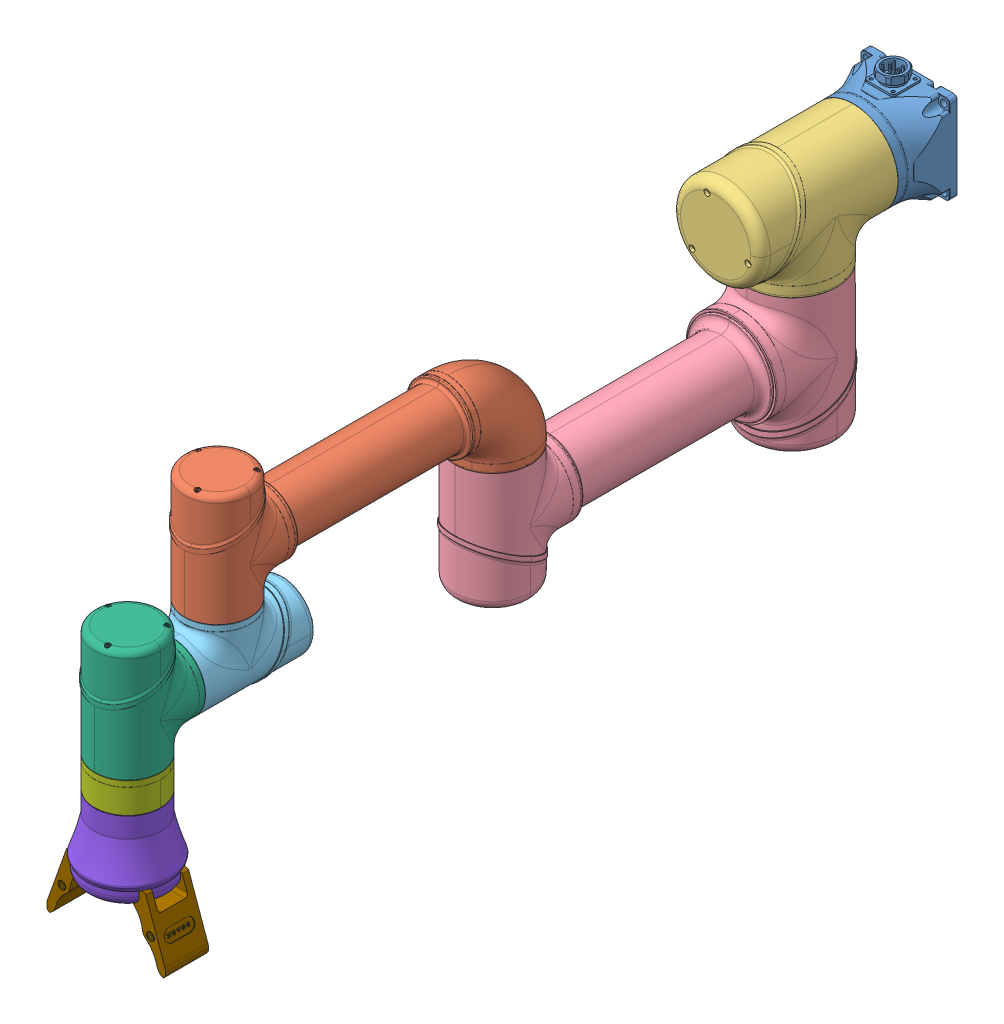
SolidWorks assembly ROCR6II, configuration 默认. Lengths in mm.
Overall size (130.91 376.35 830.22).
11 component instances, 9 part files, 15 mates.
Components (placement in the parent):
- base_link-1: base_link [默认] at origin size (130.91 130.91 60)
- forearm_link-1: forearm_link [默认] at origin size (80.19 118.2 351.88)
- shoulder_link-1: shoulder_link [默认] at origin size (92.11 107.01 149.61)
- upper_arm_link-1: upper_arm_link [默认] at origin size (92.11 149.61 386.89)
- wrist_1_link-1: wrist_1_link [默认] at origin size (72.68 81.34 118.2)
- wrist_2_link-1: wrist_2_link [默认] at origin size (70.06 118.2 81.01)
- wrist_3_link-1: wrist_3_link [默认] at origin size (66 37 66)
- end_effector-1: end_effector [默认] at (0 -186.5 787.5) x (-1 0 0) z (0 0 1) size (118.98 124.39 85.45)
  - tool_link-1: tool_link [默认] at origin size (85.45 76.02 85.45)
  - finger_link-1: finger_link [默认] at (-39.3817 59.864 0) size (37.61 64.53 43)
  - finger_link-2: finger_link [默认] at (39.3817 59.864 0) x (-1 0 0) z (0 0 -1) size (37.61 64.53 43)
Mates (geometry in assembly coordinates):
- 同心1: concentric aligned: cylinder of base_link-1 through (0 0 0) axis (0 0 -1) radius 35.5; cylinder of shoulder_link-1 through (0 0 180.501) axis (0 0 -1) radius 35.5
- 重合1: coincident anti-aligned: plane of base_link-1 through (0 0 60) normal (0 0 1); plane of shoulder_link-1 through (0 0 60) normal (0 0 -1)
- 同心2: concentric anti-aligned: cylinder of shoulder_link-1 through (0 -51 121.5) axis (0 -1 0) radius 35.5; cylinder of upper_arm_link-1 through (0 -181.501 121.5) axis (0 1 0) radius 35.5
- 重合2: coincident anti-aligned: plane of shoulder_link-1 through (-44.446 -61 128.5396) normal (0 -1 0); plane of upper_arm_link-1 through (0 -61 121.5) normal (0 1 0)
- 重合3: coincident anti-aligned: circle of forearm_link-1; plane of upper_arm_link-1 through (0 -68.5 421.5) normal (0 1 0)
- 同心3: concentric anti-aligned: cylinder of forearm_link-1 through (0 -60.5 421.5) axis (0 -1 0) radius 31; cylinder of upper_arm_link-1 through (0 -68 421.5) axis (0 1 0) radius 31
- 同心4: concentric aligned: cylinder of forearm_link-1 through (0 -126.8249 697.5) axis (0 1 0) radius 25.5; cylinder of wrist_1_link-1 through (0 -71.5 697.5) axis (0 1 0) radius 25.5
- 重合4: coincident anti-aligned: plane of forearm_link-1 through (0 -65.5 697.5) normal (0 -1 0); plane of wrist_1_link-1 through (-27.4385 -65.5 679.1662) normal (0 1 0)
- 重合5: coincident anti-aligned: plane of wrist_1_link-1 through (0 -110.5 742.5) normal (0 0 1); plane of wrist_2_link-1 through (27.4385 -92.1662 742.5) normal (0 0 -1)
- 同心5: concentric aligned: cylinder of wrist_1_link-1 through (0 -110.5 803.8249) axis (0 0 -1) radius 25.5; cylinder of wrist_2_link-1 through (0 -110.5 748.5) axis (0 0 -1) radius 25.5
- 同心6: concentric anti-aligned: cylinder of wrist_2_link-1 through (0 -216.8249 787.5) axis (0 1 0) radius 25.5; cylinder of wrist_3_link-1 through (0 -186.5 787.5) axis (0 -1 0) radius 25.5
- 重合6: coincident anti-aligned: plane of wrist_2_link-1 through (0 -155.5 787.5) normal (0 -1 0); plane of wrist_3_link-1 through (18.3338 -155.5 760.0615) normal (0 1 0)
- 同心8: concentric aligned: cylinder of wrist_3_link-1 through (0 -186.5 787.5) axis (0 -1 0) radius 15.75; cylinder of end_effector-1/tool_link-1 through (0 -186.5 787.5) axis (0 -1 0) radius 15.75
- 同心9: concentric anti-aligned: cylinder of wrist_3_link-1 through (-23.0446 -186.5 804.2689) axis (0 -1 0) radius 3; cylinder of end_effector-1/tool_link-1 through (-23.0446 -192.5 804.2689) axis (0 1 0) radius 3
- 重合8: coincident anti-aligned: plane of wrist_3_link-1 through (0 -186.5 787.5) normal (0 -1 0); plane of end_effector-1/tool_link-1 through (0 -186.5 787.5) normal (0 1 0)
